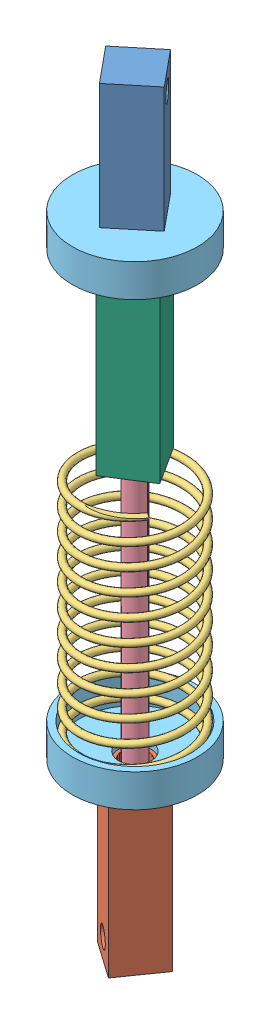
SolidWorks assembly suspension front left, configuration Default. Lengths in mm.
Overall size (25.11 117.19 25.64).
7 component instances, 6 part files, 11 mates.
Components (placement in the parent):
- ball joint-1: ball joint [Default] at (11.149 89.1959 5.7762) x (-0.63603 0 -0.771665) z (0.771665 0 -0.63603) size (7 19 7)
- ball joint down-2: ball joint down [Default] at (11.149 17.0045 5.7762) x (0.818593 0 0.574373) z (0.574373 0 -0.818593) size (7 26 7)
- Spring front-1: Spring front [Default] at (11.149 18.0045 5.7762) x (0.824379 0 0.566038) z (-0.566038 0 0.824379) size (17.22 38.53 19.28)
- suspension shaft-1: suspension shaft [Default] at (11.149 62.0045 5.7762) x (0.673138 0 -0.739517) z (-0.739517 0 -0.673138) size (3 65 3)
- washer-1: washer [Default] at (11.149 17.0045 5.7762) x (-0.137944 0 -0.99044) z (0.99044 0 -0.137944) size (19 5 19)
- washer-2: washer [Default] at (11.149 89.1959 5.7762) x (-0.982578 0 -0.185852) z (-0.185852 0 0.982578) size (19 5 19)
- suspension shaft 1-1: suspension shaft 1 [Default] at (11.149 98.1959 5.7762) x (-0.840918 0 0.541163) z (0.541163 0 0.840918) size (7 42 7)
Mates (geometry in assembly coordinates):
- Concentric1: concentric aligned: cylinder of ball joint down-2 through (11.149 -2.9955 5.7762) axis (0 1 0) radius 2; cylinder of suspension shaft-1 through (11.149 -2.9955 5.7762) axis (0 1 0) radius 1.5
- Concentric3: concentric anti-aligned: cylinder of suspension shaft-1 through (11.149 -2.9955 5.7762) axis (0 1 0) radius 1.5; cylinder of washer-1 through (11.149 18.0045 5.7762) axis (0 -1 0) radius 9.5
- Coincident1: coincident anti-aligned: plane of ball joint down-2 through (11.149 17.0045 5.7762) normal (0 1 0); plane of washer-1 through (11.149 17.0045 5.7762) normal (0 -1 0)
- Coincident2: coincident anti-aligned: plane of ball joint-1 through (11.149 89.1959 5.7762) normal (0 -1 0); plane of washer-2 through (11.149 89.1959 5.7762) normal (0 1 0)
- Coincident8: coincident anti-aligned: plane of Spring front-1 through (11.149 18.0045 5.7762) normal (0 -1 0); plane of washer-1 through (11.149 18.0045 5.7762) normal (0 1 0)
- Concentric7: concentric aligned: line of Spring front-1 through (11.149 18.0045 5.7762) axis (0 1 0); cylinder of suspension shaft-1 through (11.149 -2.9955 5.7762) axis (0 1 0) radius 1.5
- Concentric8: concentric aligned: cylinder of washer-2 through (11.149 88.1959 5.7762) axis (0 1 0) radius 2.5; cylinder of suspension shaft 1-1 through (11.149 88.1959 5.7762) axis (0 1 0) radius 2
- Concentric9: concentric anti-aligned: cylinder of ball joint-1 through (11.149 102.1959 5.7762) axis (0 -1 0) radius 2; cylinder of washer-2 through (11.149 88.1959 5.7762) axis (0 1 0) radius 2.5
- Coincident9: coincident anti-aligned: plane of washer-2 through (11.149 88.1959 5.7762) normal (0 -1 0); plane of suspension shaft 1-1 through (11.149 88.1959 5.7762) normal (0 1 0)
- Coincident10: coincident anti-aligned: plane of ball joint down-2 through (15.5897 -2.9955 -6.6463) normal (0 1 0); plane of suspension shaft-1 through (11.149 -2.9955 5.7762) normal (0 -1 0)
- Concentric10: concentric aligned: cylinder of suspension shaft-1 through (11.149 -2.9955 5.7762) axis (0 1 0) radius 1.5; cylinder of suspension shaft 1-1 through (11.149 56.1959 5.7762) axis (0 1 0) radius 2
